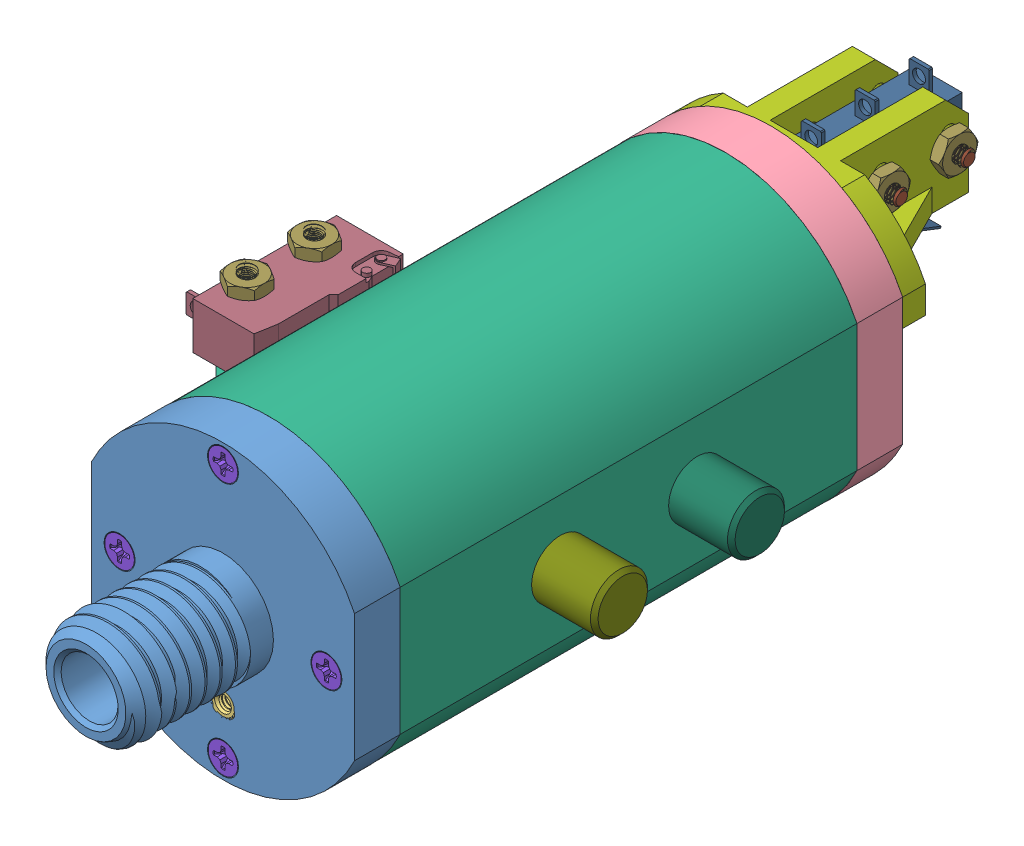
SolidWorks assembly Wing Fold Mechanism Body, configuration Default. Lengths in mm.
Overall size (59.65 40.64 121.3).
43 component instances, 16 part files, 0 mates.
Components (placement in the parent):
- Wing Fold Mechanism Upper Cap-1: Wing Fold Mechanism Upper Cap [Default] at origin size (36.58 40.64 28.08)
  - Wing Fold Mechanism Upper Cap-1: Wing Fold Mechanism Upper Cap [Default] at origin size (36.58 40.64 28.08)
  - 6338K411-1: 6338K411 [Default] at (0 0 55.5625) x (1 0 0) z (0 -1 0) size (12.7 6.35 12.7)
  - 93365A112-1: 93365A112 [Default] at (0 -11.1125 61.9125) x (1 0 0) z (0 -1 0) size (3.58 4.78 3.58)
- Wing Fold Mechanism Lower Cap-1: Wing Fold Mechanism Lower Cap [Default] at origin size (36.58 40.64 13.97)
  - Wing Fold Mechanism Lower Cap-1: Wing Fold Mechanism Lower Cap [Default] at origin size (36.58 40.64 13.97)
  - 6338K411 (1)-1: 6338K411 (1) [Default] at (0 0 -7.9375) x (1 0 0) z (0 1 0) size (12.7 6.35 12.7)
  - 93365A112-1: 93365A112 [Default] at (11.938 11.43 -14.2875) x (1 0 0) z (0 1 0) size (3.58 4.78 3.58)
  - 93365A112-2: 93365A112 [Default] at (-11.938 11.43 -14.2875) x (1 0 0) z (0 1 0) size (3.58 4.78 3.58)
- Wing Fold Mechanism Main Shell-1: Wing Fold Mechanism Main Shell [Default] at origin size (46.86 40.64 63.5)
  - Wing Fold Mechanism Main Body-1: Wing Fold Mechanism Main Body [Default] at origin size (46.86 40.64 63.5)
  - 93365A112-1: 93365A112 [Default] at (-14.378 0 55.5625) x (1 0 0) z (0 -1 0) size (3.58 4.78 3.58)
  - 93365A112-2: 93365A112 [Default] at (0 17.68 55.5625) x (1 0 0) z (0 -1 0) size (3.58 4.78 3.58)
  - 93365A112-3: 93365A112 [Default] at (14.378 0 55.5625) x (1 0 0) z (0 -1 0) size (3.58 4.78 3.58)
  - 93365A112-4: 93365A112 [Default] at (0 -17.68 55.5625) x (1 0 0) z (0 -1 0) size (3.58 4.78 3.58)
  - 93365A112-5: 93365A112 [Default] at (-14.378 0 -7.9375) x (1 0 0) z (0 1 0) size (3.58 4.78 3.58)
  - 93365A112-6: 93365A112 [Default] at (14.378 0 -7.9375) x (1 0 0) z (0 1 0) size (3.58 4.78 3.58)
  - 93365A112-7: 93365A112 [Default] at (0 -17.68 -7.9375) x (1 0 0) z (0 1 0) size (3.58 4.78 3.58)
  - 93365A112-8: 93365A112 [Default] at (0 17.68 -7.9375) x (1 0 0) z (0 1 0) size (3.58 4.78 3.58)
- Wing Fold Mechanism Locking Limit Switch Bracket-1: Wing Fold Mechanism Locking Limit Switch Bracket [Default] at origin size (36.58 12.7 20.96)
- 96640A027-1: 96640A027 [Default] at (-14.378 0 60.6171) size (4.11 4.11 12.73)
- 96640A027-2: 96640A027 [Default] at (0 -17.68 60.6171) size (4.11 4.11 12.73)
- 96640A027-3: 96640A027 [Default] at (0 17.68 60.6171) size (4.11 4.11 12.73)
- 96640A027-4: 96640A027 [Default] at (14.378 0 60.6171) size (4.11 4.11 12.73)
- 96640A027-5: 96640A027 [Default] at (0 -17.68 -12.9921) x (1 0 0) z (0 0 -1) size (4.11 4.11 12.73)
- 96640A027-6: 96640A027 [Default] at (0 17.68 -12.9921) x (1 0 0) z (0 0 -1) size (4.11 4.11 12.73)
- 96640A027-7: 96640A027 [Default] at (14.378 0 -12.9921) x (1 0 0) z (0 0 -1) size (4.11 4.11 12.73)
- 96640A027-8: 96640A027 [Default] at (-14.378 0 -12.9921) x (1 0 0) z (0 0 -1) size (4.11 4.11 12.73)
- 91249A050-1: 91249A050 [Default] at (-11.938 11.43 -11.1125) x (1 0 0) z (0 0 -1) size (4.25 4.24 8)
- 91249A050-2: 91249A050 [Default] at (11.938 11.43 -11.1125) x (1 0 0) z (0 0 -1) size (4.25 4.24 8)
- 7658K15-1: 7658K15 [Default] at (-0.0508 14.2684 -27.6606) x (0 0 -1) z (-1 0 0) size (19.99 19.56 6.5)
- 91249A060-1: 91249A060 [Default] at (9.398 11.9062 -23.0505) x (0 0 -1) z (-1 0 0) size (12.29 12.29 20.87)
- 91249A060-2: 91249A060 [Default] at (9.398 11.9062 -32.4485) x (0 0 -1) z (-1 0 0) size (12.29 12.29 20.87)
- 91841A003-1: 91841A003 [Default] at (7.2708 11.9062 -23.0505) x (0 -1 0) z (0 0 1) size (4.76 1.72 5.5)
- 91841A003-2: 91841A003 [Default] at (7.2708 11.9062 -32.4485) x (0 -1 0) z (0 0 1) size (4.76 1.72 5.5)
- 7658K16-1: 7658K16 [Default] at (-28.3972 8.1042 27.7241) x (0 0 1) z (0 1 0) size (19.99 24.56 6.5)
- 7658K16-2: 7658K16 [Default] at (-28.3972 -8.1042 27.7241) x (0 0 1) z (0 1 0) size (19.99 24.56 6.5)
- 91249A066-1: 91249A066 [Default] at (-26.035 14.0446 23.1521) x (1 0 0) z (0 -1 0) size (12.46 12.46 36.26)
- 91249A066-2: 91249A066 [Default] at (-26.035 14.0446 32.512) x (1 0 0) z (0 -1 0) size (12.46 12.46 36.26)
- 91841A003-3: 91841A003 [Default] at (-26.035 12.1491 23.1521) x (-1 0 0) z (0 0 -1) size (4.76 1.72 5.5)
- 91841A003-4: 91841A003 [Default] at (-26.035 12.1491 32.512) x (-1 0 0) z (0 0 -1) size (4.76 1.72 5.5)
- 84835A44-1: 84835A44 [Default] at (17.1196 0 14.2875) x (0 1 0) z (0 0 -1) size (9.53 19.76 9.53)
- 84835A36-1: 84835A36 [Default] at (17.1196 0 33.3375) x (0 1 0) z (0 0 -1) size (9.53 19.76 9.53)
